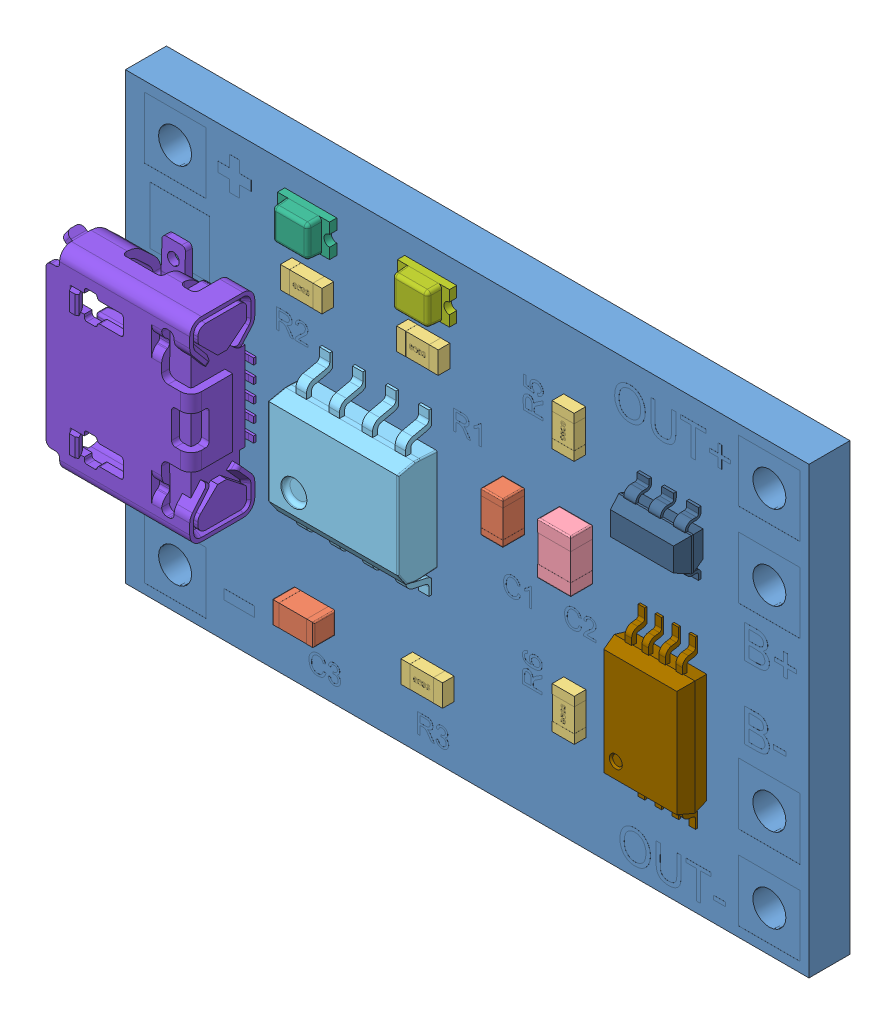
SolidWorks assembly Lipo Charger - With Load Protection.stp, configuration Default. Lengths in mm.
Overall size (26.91 17.09 4.28).
15 component instances, 10 part files, 0 mates.
Components (placement in the parent):
- bOARD.stp-1: bOARD.stp [Default] at origin size (26.26 17.09 1.68)
- 0603 Capacitor.stp-1: 0603 Capacitor.stp [Default] at (1.3663 2.3089 1.5723) x (0 -1 0) z (0 0 1) size (1.6 0.84 0.84)
- 0603 Resistor.stp-1: 0603 Resistor.stp [Default] at (-2.0999 -6.1665 1.5723) size (1.6 0.85 0.56)
- 0603 Resistor.stp-2: 0603 Resistor.stp [Default] at (-6.7314 4.6411 1.5723) size (1.6 0.85 0.56)
- 0805 Capacitor.stp-1: 0805 Capacitor.stp [Default] at (3.543 2.3802 1.5723) x (0 -1 0) z (0 0 1) size (2.01 1.27 0.84)
- 0603 Capacitor.stp-2: 0603 Capacitor.stp [Default] at (-6.6654 -6.2522 1.5723) size (1.6 0.84 0.84)
- SOIC-8-150.stp-1: SOIC-8-150.stp [Default] at (-3.5116 0.0462 2.4718) x (-1 0 0) z (0 1 0) size (5 1.75 6.2)
- LED - 0805 - Blue.stp-1: LED - 0805 - Blue.stp [Default] at (-6.7354 7.0496 1.5448) size (2 1.25 0.83)
- LED - 0805 - Red.stp-1: LED - 0805 - Red.stp [Default] at (-0.6772 7.1069 1.5448) x (-1 0 0) z (0 0 1) size (2 1.25 0.83)
- 0603 Resistor.stp-3: 0603 Resistor.stp [Default] at (-2.2661 4.8273 1.5723) size (1.6 0.85 0.56)
- USB - Micro.stp-1: USB - Micro.stp [Default] at (-7.8617 -2.8878 1.1998) x (0 -1 0) z (-1 0 0) size (7.92 3.01 5.67)
- tsop8.stp-1: tsop8.stp [Default] at (7.7511 -2.5035 1.4748) x (0 1 0) z (0 0 1) size (6.4 3.1 1.2)
- sot-23-6-2.stp-1: sot-23-6-2.stp [Default] at (7.8055 3.8715 1.5748) x (0 1 0) z (0 0 1) size (2.43 2.79 1.09)
- 0603 Resistor.stp-4: 0603 Resistor.stp [Default] at (4.561 -4.8365 1.5723) x (0 1 0) z (0 0 1) size (1.6 0.85 0.56)
- 0603 Resistor.stp-5: 0603 Resistor.stp [Default] at (3.7053 6.1769 1.5723) x (0 -1 0) z (0 0 1) size (1.6 0.85 0.56)
